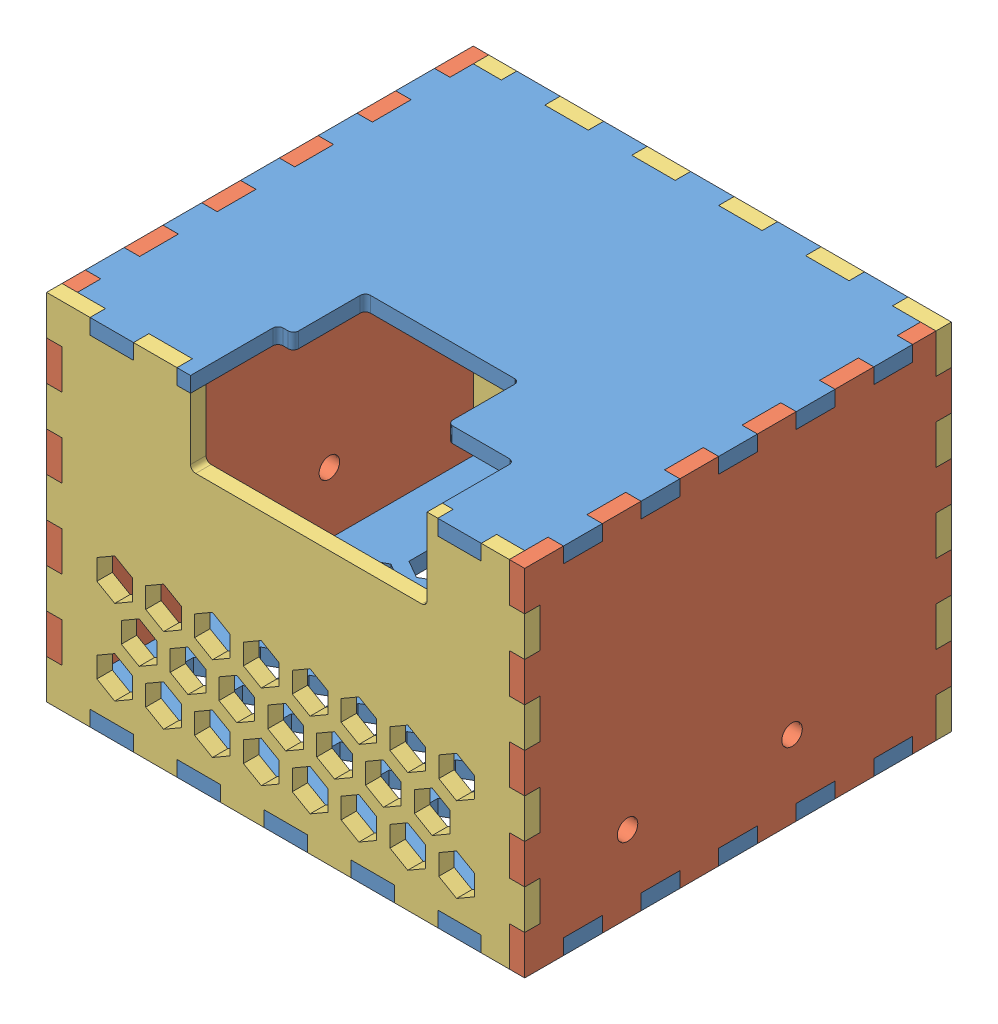
SolidWorks assembly DC-DC Boost 400W, configuration Default. Lengths in mm.
Overall size (93 69 83).
6 component instances, 3 part files, 18 mates.
Components (placement in the parent):
- unten_oben-1: unten_oben [unten] at (-9.1679 54.5344 97.0759) size (93 3 83)
- rechts_links-1: rechts_links [rechts] at (83.8319 123.5344 97.0097) x (0 0 -1) z (0 1 0) size (83 3 69)
- vorne_hinten-1: vorne_hinten [vorne] at (-9.1679 123.5344 97.0097) x (1 0 0) z (0 1 0) size (93 3 69)
- unten_oben-3: unten_oben [oben] at (-9.1679 120.5343 97.0759) size (93 3 83)
- rechts_links-4: rechts_links [links] at (-9.1679 123.5344 14.0114) x (0 0 1) z (0 1 0) size (83 3 69)
- vorne_hinten-4: vorne_hinten [hinten] at (83.8319 123.5344 14.0104) x (-1 0 0) z (0 1 0) size (93 3 69)
Mates (geometry in assembly coordinates):
- Deckungsgleich11: coincident aligned: plane of unten_oben-1 through (83.8319 57.5344 89.4649) normal (1 0 0); plane of rechts_links-1 through (83.8319 123.5344 97.0097) normal (1 0 0)
- Deckungsgleich12: coincident aligned: plane of unten_oben-1 through (66.9231 57.5344 97.0097) normal (0 0 1); plane of rechts_links-1 through (80.8319 62.2019 97.0097) normal (0 0 1)
- Deckungsgleich13: coincident aligned: plane of unten_oben-1 through (-9.1679 54.5344 97.0759) normal (0 -1 0); plane of rechts_links-1 through (80.8319 54.5344 97.0097) normal (0 -1 0)
- Deckungsgleich14: coincident aligned: plane of unten_oben-1 through (-9.1679 57.5344 89.4649) normal (-1 0 0); plane of ? through (-9.1679 123.5344 97.0097) normal (-1 0 0)
- Deckungsgleich17: coincident aligned: plane of unten_oben-1 through (-9.1679 54.5344 97.0759) normal (0 -1 0); plane of ? through (-9.1679 54.5344 51.737) normal (0 -1 0)
- Deckungsgleich19: coincident aligned: plane of unten_oben-1 through (-0.7135 57.5344 97.0097) normal (0 0 1); plane of ? through (-9.1679 62.2019 97.0097) normal (0 0 1)
- Deckungsgleich20: coincident anti-aligned: plane of unten_oben-1 through (24.6507 57.5344 94.0097) normal (0 0 1); plane of vorne_hinten-1 through (-9.1679 123.5344 94.0097) normal (0 0 -1)
- Deckungsgleich21: coincident aligned: plane of rechts_links-1 through (83.8319 123.5344 97.0097) normal (1 0 0); plane of vorne_hinten-1 through (83.8319 69.8679 94.0097) normal (1 0 0)
- Deckungsgleich22: coincident aligned: plane of unten_oben-1 through (-9.1679 54.5344 97.0759) normal (0 -1 0); plane of vorne_hinten-1 through (75.3775 54.5344 94.0097) normal (0 -1 0)
- Deckungsgleich29: coincident aligned: plane of rechts_links-1 through (80.8319 123.5343 81.9188) normal (0 1 0); plane of unten_oben-3 through (-9.1679 123.5343 97.0759) normal (0 1 0)
- Deckungsgleich30: coincident aligned: plane of rechts_links-1 through (83.8319 123.5344 97.0097) normal (1 0 0); plane of unten_oben-3 through (83.8319 123.5343 59.2831) normal (1 0 0)
- Deckungsgleich31: coincident aligned: plane of vorne_hinten-1 through (-9.1679 123.5344 97.0097) normal (0 0 1); plane of unten_oben-3 through (66.9231 123.5343 97.0097) normal (0 0 1)
- Deckungsgleich32: coincident aligned: plane of unten_oben-3 through (-9.1679 123.5343 89.4649) normal (-1 0 0); plane of rechts_links-4 through (-9.1679 123.5344 14.0114) normal (-1 0 0)
- Deckungsgleich33: coincident aligned: plane of unten_oben-3 through (-9.1679 123.5343 97.0759) normal (0 1 0); plane of rechts_links-4 through (-6.1679 123.5343 44.193) normal (0 1 0)
- Deckungsgleich34: coincident aligned: plane of vorne_hinten-1 through (-9.1679 123.5344 97.0097) normal (0 0 1); plane of rechts_links-4 through (-6.1679 115.868 97.0097) normal (0 0 1)
- Deckungsgleich35: coincident aligned: plane of unten_oben-1 through (66.9231 57.5344 14.0104) normal (0 0 -1); plane of vorne_hinten-4 through (83.8319 123.5344 14.0104) normal (0 0 -1)
- Deckungsgleich36: coincident aligned: plane of rechts_links-1 through (83.8319 123.5344 97.0097) normal (1 0 0); plane of vorne_hinten-4 through (83.8319 62.2004 17.0104) normal (1 0 0)
- Deckungsgleich37: coincident aligned: plane of unten_oben-1 through (-9.1679 54.5344 97.0759) normal (0 -1 0); plane of vorne_hinten-4 through (83.8319 54.5344 17.0104) normal (0 -1 0)
